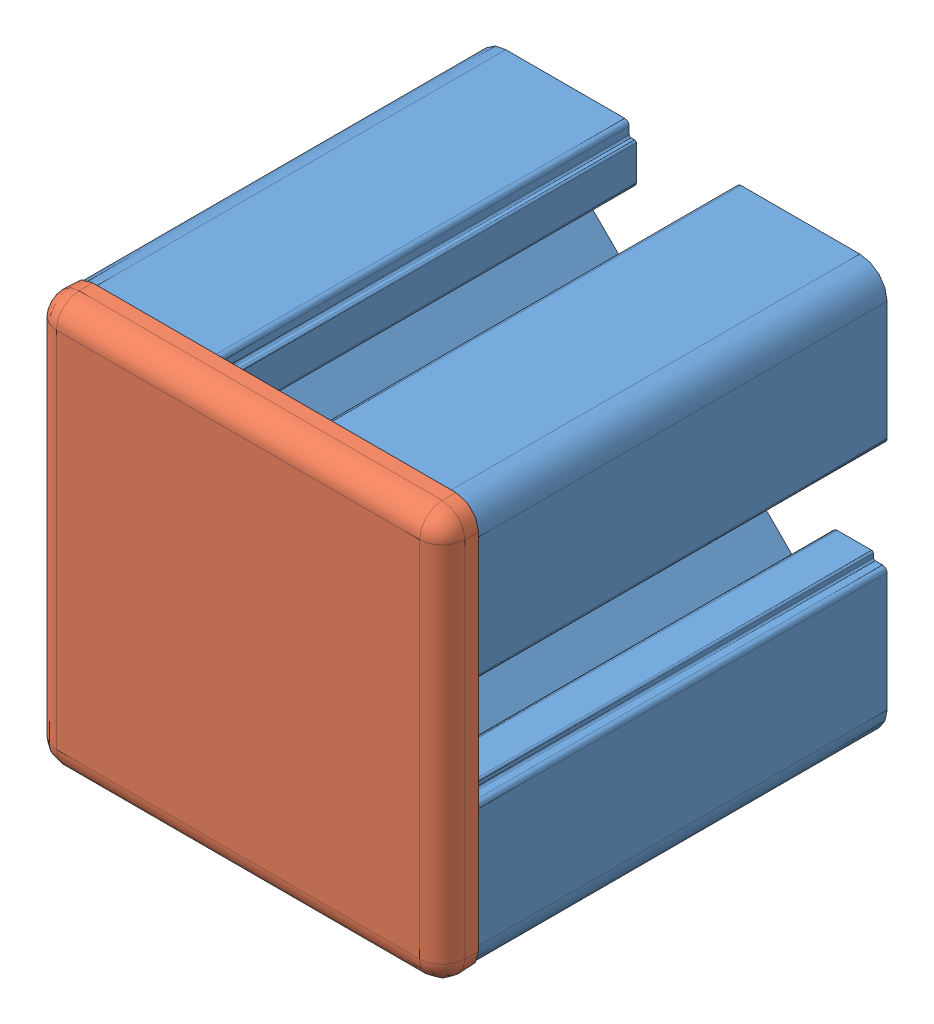
SolidWorks assembly Заглушка45х45СБ, configuration По умолчанию. Lengths in mm.
Overall size (45 45 49).
2 component instances, 2 part files, 6 mates.
Components (placement in the parent):
- 45х45 заглушка-1: 45х45 заглушка [По умолчанию] at origin size (45 45 45)
- Заглушка торцевая 45х45-1: Заглушка торцевая 45х45 [По умолчанию] at (0 0 47) x (0 0 -1) z (1 0 0) size (12 45 45)
Mates (geometry in assembly coordinates):
- Совпадение2: coincident: point of 45х45 заглушка-1
- Параллельность1: parallel anti-aligned: plane of 45х45 заглушка-1 through (0 -22.5 45) normal (0 -1 0)
- Совпадение4: coincident anti-aligned: plane of 45х45 заглушка-1 through (0 0 0) normal (0 0 -1)
- Совпадение5: coincident anti-aligned: plane of 45х45 заглушка-1 through (0 0 45) normal (0 0 1); plane of Заглушка торцевая 45х45-1 through (-22.5 -22.5 45) normal (0 0 -1)
- Совпадение6: coincident aligned: plane of 45х45 заглушка-1 through (22.5 0 45) normal (1 0 0); plane of Заглушка торцевая 45х45-1 through (22.5 20 46.5) normal (1 0 0)
- Совпадение7: coincident aligned: plane of 45х45 заглушка-1 through (0 22.5 45) normal (0 1 0); plane of Заглушка торцевая 45х45-1 through (-22.5 22.5 46.5) normal (0 1 0)
